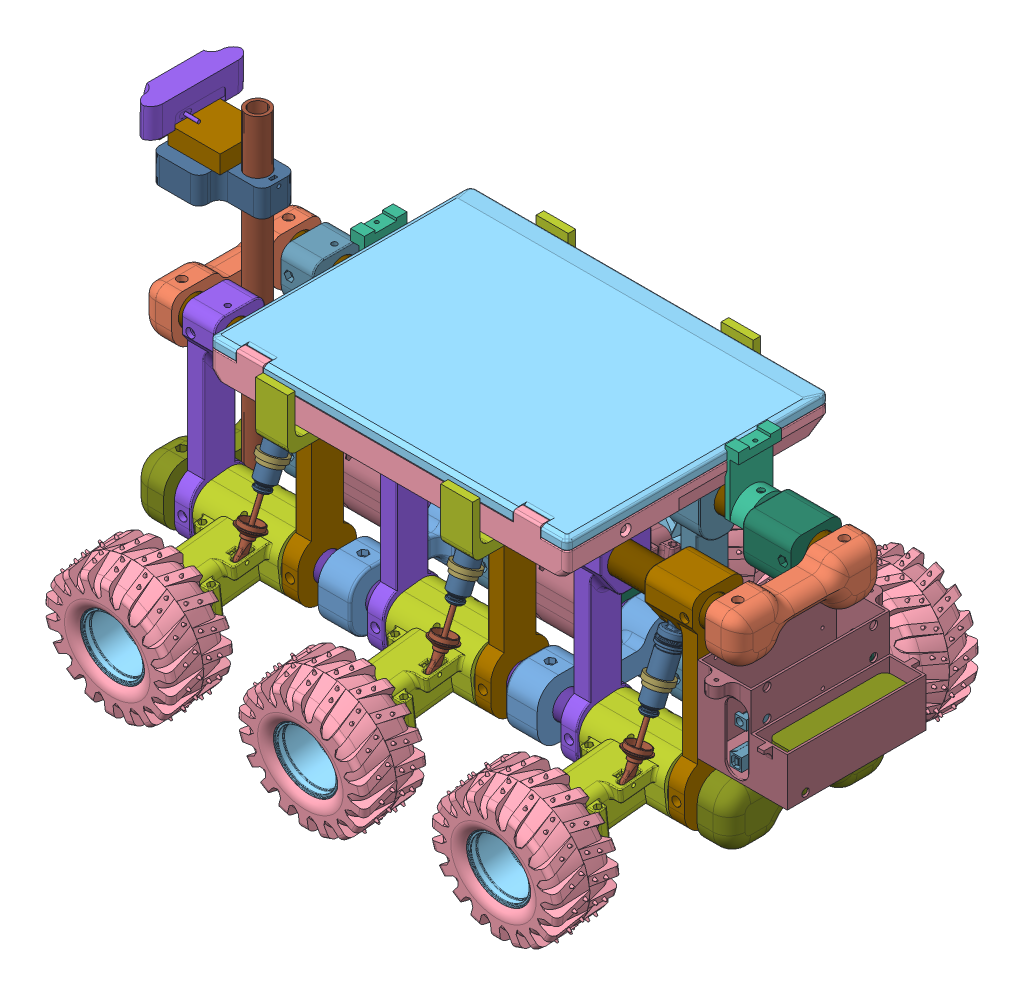
SolidWorks assembly main, configuration Default. Lengths in mm.
Overall size (673.66 443.73 565.58).
139 component instances, 35 part files, 83 mates.
Components (placement in the parent):
- ArmLeft-4: ArmLeft [Default] at (93.4852 140.0637 -467.7732) x (-1 0.000035 -0.000047) z (-0.000059 -0.599103 0.800672) size (161.81 187.08 295.86) (flexible)
  - Pololu_GearMotor_37Dmm-1: Pololu_GearMotor_37Dmm [Default] at (-21.99 -13.2291 218.2431) x (0.802337 0.514869 0.301937) z (0.000051 0.505806 -0.862647) size (51.49 51.49 82.3)
    - Pololu_ShaftGearMotor6mm-1: Pololu_ShaftGearMotor6mm [Default] at (9.8861 24.7007 16.6991) x (0.930815 0.36549 0) z (0 0 1) size (6 6 22)
    - Pololu_GearMotor_37Dmm-1: Pololu_GearMotor_37Dmm [Default] at (5.7082 30.3171 38.6991) x (-0.802354 -0.596848 0) z (0 0 -1) size (36.8 36.8 66.8)
  - BallBearing16412RS-1: BallBearing16412RS [Default] at (40.4709 -35.6395 240.9945) x (0.000054 0.419689 -0.907668) z (-1 0 -0.000059) size (50.8 50.8 14.29)
  - BallBearing16412RS-2: BallBearing16412RS [Default] at (-24.815 130.5388 213.2998) x (0.000042 -0.703492 -0.710704) z (-1 0 -0.000059) size (50.8 50.8 14.29)
  - Wheel-1: Wheel [Default] at (-14.2771 -41.8136 234.87) x (-0.938256 -0.298401 -0.175021) z (-0.000051 -0.505806 0.862647) size (126 126 62.61)
    - Tire-1: Tire [Varsayılan] at origin size (126 126 62.61)
    - tire_rim-1: tire_rim [Varsayılan] at (-6.6946 4.5427 -50) size (60 60 50)
  - HexWheelAdapter12_6mm-1: HexWheelAdapter12_6mm [Default] at (0.6857 -20.0769 202.4063) x (-0.115347 -0.856887 -0.502435) z (0.000051 0.505806 -0.862647) size (13.44 15.09 20)
  - MotorHolder1-1: MotorHolder1 [Default] at (-39.3143 -104.2251 201.6101) x (0.000051 0.505806 -0.862647) z (-1 0 -0.000059) size (107 55 80)
  - SuspensionLeft^ArmLeft-2: SuspensionLeft^ArmLeft [Default] at (43.4958 309.0701 -179.2653) x (-0.000047 -0.599103 0.800672) z (1 0 0.000059) size (55 192.5 30) (virtual)
  - Suspension-1: Suspension [Default] at (-42.2924 208.9334 -168.1241) x (0.000047 0.599103 -0.800672) z (-1 0 -0.000059) size (55 192.5 45)
  - ShockAbsorber-2: ShockAbsorber [Default] at (53.0553 208.387 150.3852) x (-0.438818 0.639066 0.631692) z (0.898576 0.312053 0.308519) size (127.39 56.5 78.28) (flexible)
    - ShockBody^ShockAbsorber-2: ShockBody^ShockAbsorber [Default] at (-177.2049 125.2783 -170.9566) x (-0.238903 0.964011 -0.116656) z (-0.43878 0 0.898594) size (22.02 74.55 22) (virtual)
    - Part4^ShockAbsorber-1: Part4^ShockAbsorber [Default] at (-177.4143 124.7536 -171.0588) x (0.238903 -0.964011 0.116656) z (0.43878 0 -0.898594) size (24 84.5 24) (virtual)
    - SpringAdjuster^ShockAbsorber-1: SpringAdjuster^ShockAbsorber [Default] at (-160.5945 130.1166 -162.8457) x (0.454686 -0.068682 -0.888) z (-0.207035 0.961561 -0.18038) size (24.5 8.5 24.5) (virtual)
    - Spring^ShockAbsorber-2: Spring^ShockAbsorber [Default] at (-75.3079 244.2893 -165.8313) x (-0.870144 -0.24964 -0.424888) z (0.492715 -0.424888 -0.759409) (virtual)
- ArmLeft-1: ArmLeft [Default] at (455.6977 21.2748 -292.1899) x (-1 -0.000003 0.000059) z (-0.000059 0.045994 -0.998942) size (177.35 270.46 190.89) (flexible)
  - Pololu_GearMotor_37Dmm-1: Pololu_GearMotor_37Dmm [Default] at (-21.9766 -0.1884 -7.3506) x (0.802352 -0.595823 0.035007) z (-0.000059 0.058573 0.998283) size (51.49 51.49 82.3)
    - Pololu_ShaftGearMotor6mm-1: Pololu_ShaftGearMotor6mm [Default] at (9.8861 24.7007 16.6991) x (0.930815 0.36549 0) z (0 0 1) size (6 6 22)
    - Pololu_GearMotor_37Dmm-1: Pololu_GearMotor_37Dmm [Default] at (5.7082 30.3171 38.6991) x (-0.802354 -0.596848 0) z (0 0 -1) size (36.8 36.8 66.8)
  - BallBearing16412RS-1: BallBearing16412RS [Default] at (40.4871 -19.893 -32.5036) x (-0.000056 0.32881 0.944396) z (-1 0 -0.000059) size (50.8 50.8 14.29)
  - BallBearing16412RS-2: BallBearing16412RS [Default] at (-24.8084 -120.1687 102.8691) x (-0.000001 0.99975 0.022349) z (-1 0 -0.000059) size (50.8 50.8 14.29)
  - Wheel-1: Wheel [Default] at (10.2673 23.7342 -37.6028) x (0.772436 0.634004 -0.037154) z (0.000059 -0.058573 -0.998283) size (126 126 62.61)
    - Tire-1: Tire [Varsayılan] at origin size (126 126 62.61)
    - tire_rim-1: tire_rim [Varsayılan] at (-6.6946 4.5427 -50) size (60 60 50)
  - HexWheelAdapter12_6mm-1: HexWheelAdapter12_6mm [Default] at (0.6975 14.3033 2.017) x (0.915591 -0.401418 0.023607) z (-0.000059 0.058573 0.998283) size (13.44 15.09 20)
  - MotorHolder1-1: MotorHolder1 [Default] at (-39.2997 84.7168 -44.0666) x (-0.000059 0.058573 0.998283) z (-1 0 -0.000059) size (107 55 80)
  - SuspensionLeft^ArmLeft-2: SuspensionLeft^ArmLeft [Default] at (43.4554 -44.446 502.7733) x (0.000059 0.045994 -0.998942) z (1 0 0.000059) size (55 192.5 30) (virtual)
  - Suspension-1: Suspension [Default] at (-42.3282 32.1448 437.3049) x (-0.000059 -0.045994 0.998942) z (-1 0 -0.000059) size (55 192.5 45)
  - ShockAbsorber-2: ShockAbsorber [Default] at (55.2647 -132.4405 202.2145) x (-0.43878 -0.898535 -0.010332) z (0.898595 -0.438752 -0.004979) size (123.94 75.92 76.38) (flexible)
    - ShockBody^ShockAbsorber-2: ShockBody^ShockAbsorber [Default] at (-179.6479 111.9864 -174.6116) x (-0.383839 0.904178 -0.187427) z (-0.43878 0 0.898594) size (22.02 74.55 22) (virtual)
    - Part4^ShockAbsorber-1: Part4^ShockAbsorber [Default] at (-180.0609 111.2784 -174.8133) x (0.383839 -0.904178 0.187427) z (0.43878 0 -0.898594) size (24 84.5 24) (virtual)
    - SpringAdjuster^ShockAbsorber-1: SpringAdjuster^ShockAbsorber [Default] at (-164.0284 119.9213 -166.9847) x (0.465012 -0.064419 -0.882957) z (-0.351603 0.901881 -0.250972) size (24.5 8.5 24.5) (virtual)
    - Spring^ShockAbsorber-2: Spring^ShockAbsorber [Default] at (-75.3079 244.2893 -165.8313) x (-0.870144 -0.24964 -0.424888) z (0.492715 -0.424888 -0.759409) (virtual)
- ArmLeft-2: ArmLeft [Default] at (274.2727 21.2748 -292.1899) x (-1 -0.000003 0.000059) z (-0.000059 0.045994 -0.998942) size (177.35 273.11 192.19) (flexible)
  - Pololu_GearMotor_37Dmm-1: Pololu_GearMotor_37Dmm [Default] at (-21.9767 -2.2828 -6.8251) x (0.802352 -0.595084 0.045897) z (-0.000059 0.07682 0.997045) size (51.49 51.49 82.3)
    - Pololu_ShaftGearMotor6mm-1: Pololu_ShaftGearMotor6mm [Default] at (9.8861 24.7007 16.6991) x (0.930815 0.36549 0) z (0 0 1) size (6 6 22)
    - Pololu_GearMotor_37Dmm-1: Pololu_GearMotor_37Dmm [Default] at (5.7082 30.3171 38.6991) x (-0.802354 -0.596848 0) z (0 0 -1) size (36.8 36.8 66.8)
  - BallBearing16412RS-1: BallBearing16412RS [Default] at (40.4871 -19.893 -32.5036) x (-0.000056 0.32881 0.944396) z (-1 0 -0.000059) size (50.8 50.8 14.29)
  - BallBearing16412RS-2: BallBearing16412RS [Default] at (-24.8084 -120.1687 102.8691) x (-0.000001 0.99975 0.022349) z (-1 0 -0.000059) size (50.8 50.8 14.29)
  - Wheel-1: Wheel [Default] at (10.2673 21.0826 -37.5097) x (0.772437 0.633218 -0.048742) z (0.000059 -0.07682 -0.997045) size (126 126 62.61)
    - Tire-1: Tire [Varsayılan] at origin size (126 126 62.61)
    - tire_rim-1: tire_rim [Varsayılan] at (-6.6946 4.5427 -50) size (60 60 50)
  - HexWheelAdapter12_6mm-1: HexWheelAdapter12_6mm [Default] at (0.6975 12.3777 2.276) x (0.91559 -0.40092 0.030944) z (-0.000059 0.07682 0.997045) size (13.44 15.09 20)
  - MotorHolder1-1: MotorHolder1 [Default] at (-39.2997 81.9368 -45.0877) x (-0.000059 0.07682 0.997045) z (-1 0 -0.000059) size (107 55 80)
  - SuspensionLeft^ArmLeft-2: SuspensionLeft^ArmLeft [Default] at (43.4554 -44.446 502.7733) x (0.000059 0.045994 -0.998942) z (1 0 0.000059) size (55 192.5 30) (virtual)
  - Suspension-1: Suspension [Default] at (-42.3282 32.1448 437.3049) x (-0.000059 -0.045994 0.998942) z (-1 0 -0.000059) size (55 192.5 45)
  - ShockAbsorber-2: ShockAbsorber [Default] at (22.1166 -132.4405 202.2126) x (-0.43878 -0.898535 -0.010332) z (0.898595 -0.438752 -0.004979) size (124.68 76.16 76.74) (flexible)
    - ShockBody^ShockAbsorber-2: ShockBody^ShockAbsorber [Default] at (-194.1718 111.9381 -144.8147) x (-0.382875 0.904684 -0.186957) z (-0.43878 0 0.898594) size (22.02 74.55 22) (virtual)
    - Part4^ShockAbsorber-1: Part4^ShockAbsorber [Default] at (-193.8798 111.6005 -144.6721) x (0.382875 -0.904684 0.186957) z (0.43878 0 -0.898594) size (24 84.5 24) (virtual)
    - SpringAdjuster^ShockAbsorber-1: SpringAdjuster^ShockAbsorber [Default] at (-178.5439 119.8524 -137.1837) x (0.464944 -0.064455 -0.882991) z (-0.350641 0.902385 -0.250502) size (24.5 8.5 24.5) (virtual)
    - Spring^ShockAbsorber-2: Spring^ShockAbsorber [Default] at (-75.3079 244.2893 -165.8313) x (-0.870144 -0.24964 -0.424888) z (0.492715 -0.424888 -0.759409) (virtual)
- Assem1^main-3: Assem1^main [Default] at (614.6197 202.709 -360.6526) x (0.43878 0.524054 0.729959) z (-0.898594 0.255894 0.356436) size (307.39 188.45 223.5) (virtual, flexible)
  - ShockAbsorber-1: ShockAbsorber [Default] at origin size (120.44 86.03 74.55) (flexible)
    - ShockBody^ShockAbsorber-2: ShockBody^ShockAbsorber [Default] at (-210.0974 33.2247 49.0022) x (0.462095 -0.857645 0.22564) z (-0.43878 0 0.898594) size (22.02 74.55 22) (virtual)
    - Part4^ShockAbsorber-1: Part4^ShockAbsorber [Default] at (-209.6006 34.0738 49.2448) x (-0.462095 0.857645 -0.22564) z (0.43878 0 -0.898594) size (24 84.5 24) (virtual)
    - SpringAdjuster^ShockAbsorber-1: SpringAdjuster^ShockAbsorber [Default] at (-224.9376 23.6143 41.7558) x (0.404743 0.061104 -0.912387) z (0.492182 -0.855465 0.161045) size (24.5 8.5 24.5) (virtual)
    - Spring^ShockAbsorber-2: Spring^ShockAbsorber [Default] at (-34.7976 -2.4454 -146.0502) x (0 1 0) z (0 0 -1) (virtual)
  - MotorHolder1-Mirror-1: MotorHolder1-Mirror [Default] at (-43.4227 -84.7919 111.9156) x (-0.778882 0.498694 -0.380325) z (0.43878 0 -0.898594) size (107 55 80)
  - BallBearing16412RS-1: BallBearing16412RS [Default] at (-127.0871 -123.0561 87.1989) x (-0.742239 0.56367 -0.362433) z (0.43878 0 -0.898594) size (50.8 50.8 14.29)
  - BallBearing16412RS-2: BallBearing16412RS [Default] at (-166.6314 -138.7613 140.5447) x (-0.66767 0.669274 -0.326021) z (0.43878 0 -0.898594) size (50.8 50.8 14.29)
  - PilarLeftMirror-1: PilarLeftMirror [Default] at (-608.0681 165.3148 -71.6688) x (0.729959 -0.583193 0.356436) z (-0.43878 0 0.898594) size (55 192.5 30)
  - PilarRightMirror-1: PilarRightMirror [Default] at (-419.6492 135.2573 -74.8966) x (-0.729959 0.583193 -0.356436) z (0.43878 0 -0.898594) size (55 192.5 45)
  - Pololu_GearMotor_37Dmm-1: Pololu_GearMotor_37Dmm [Default] at (-358.3928 -1.0018 27.8643) x (0.084596 -0.517335 -0.851592) z (0.778882 -0.498694 0.380325) size (51.49 51.49 82.3)
    - Pololu_ShaftGearMotor6mm-1: Pololu_ShaftGearMotor6mm [Default] at (9.8861 24.7007 16.6991) x (0.930815 0.36549 0) z (0 0 1) size (6 6 22)
    - Pololu_GearMotor_37Dmm-1: Pololu_GearMotor_37Dmm [Default] at (5.7082 30.3171 38.6991) x (-0.802354 -0.596848 0) z (0 0 -1) size (36.8 36.8 66.8)
  - HexWheelAdapter12_6mm-1: HexWheelAdapter12_6mm [Default] at (-334.2626 5.976 14.4134) x (0.000452 -0.605968 -0.795489) z (0.778882 -0.498694 0.380325) size (13.44 15.09 20)
  - Wheel-1: Wheel [Default] at (-357.6829 39.0349 3.1806) x (0.524924 0.850217 0.03982) z (-0.778882 0.498694 -0.380325) size (126 126 62.61)
    - Tire-1: Tire [Varsayılan] at origin size (126 126 62.61)
    - tire_rim-1: tire_rim [Varsayılan] at (-6.6946 4.5427 -50) size (60 60 50)
- Assem1^main-2: Assem1^main [Default] at (419.1947 176.319 -305.5999) x (0.43878 0.198516 0.876392) z (-0.898594 0.096934 0.427939) size (254.15 240.53 210.87) (virtual, flexible)
  - ShockAbsorber-1: ShockAbsorber [Default] at (357.3593 5.6816 -428.7668) size (96.34 119.79 62.78) (flexible)
    - ShockBody^ShockAbsorber-2: ShockBody^ShockAbsorber [Default] at (-603.8877 -2.3924 444.1635) x (0.727359 -0.587202 0.355167) z (-0.43878 0 0.898594) size (22.02 74.55 22) (virtual)
    - Part4^ShockAbsorber-1: Part4^ShockAbsorber [Default] at (-604.8865 -3.1688 443.6758) x (-0.727359 0.587202 -0.355167) z (0.43878 0 -0.898594) size (24 84.5 24) (virtual)
    - SpringAdjuster^ShockAbsorber-1: SpringAdjuster^ShockAbsorber [Default] at (-614.1511 -17.7106 439.1519) x (0.385844 0.041836 -0.921615) z (0.756772 -0.58571 0.290243) size (24.5 8.5 24.5) (virtual)
    - Spring^ShockAbsorber-2: Spring^ShockAbsorber [Default] at (-34.7976 -2.4454 -146.0502) x (0 1 0) z (0 0 -1) (virtual)
  - MotorHolder1-Mirror-1: MotorHolder1-Mirror [Default] at (-53.1417 -26.6364 91.3535) x (-0.896004 0.07587 -0.437516) z (0.43878 0 -0.898594) size (107 55 80)
  - BallBearing16412RS-1: BallBearing16412RS [Default] at (-135.4943 -159.2835 67.2773) x (-0.742239 0.56367 -0.362433) z (0.43878 0 -0.898594) size (50.8 50.8 14.29)
  - BallBearing16412RS-2: BallBearing16412RS [Default] at (-175.0386 -174.9888 120.6231) x (-0.66767 0.669274 -0.326021) z (0.43878 0 -0.898594) size (50.8 50.8 14.29)
  - PilarLeftMirror-1: PilarLeftMirror [Default] at (-661.7065 -34.8006 -113.6766) x (0.876392 -0.220918 0.427939) z (-0.43878 0 0.898594) size (55 192.5 30)
  - PilarRightMirror-1: PilarRightMirror [Default] at (-474.6757 2.8793 -117.5822) x (-0.876392 0.220918 -0.427939) z (0.43878 0 -0.898594) size (55 192.5 45)
  - Pololu_GearMotor_37Dmm-1: Pololu_GearMotor_37Dmm [Default] at (-372.4617 -89.0874 5.1782) x (0.311366 -0.595128 -0.74086) z (0.896004 -0.07587 0.437516) size (51.49 51.49 82.3)
    - Pololu_ShaftGearMotor6mm-1: Pololu_ShaftGearMotor6mm [Default] at (9.8861 24.7007 16.6991) x (0.930815 0.36549 0) z (0 0 1) size (6 6 22)
    - Pololu_GearMotor_37Dmm-1: Pololu_GearMotor_37Dmm [Default] at (5.7082 30.3171 38.6991) x (-0.802354 -0.596848 0) z (0 0 -1) size (36.8 36.8 66.8)
  - HexWheelAdapter12_6mm-1: HexWheelAdapter12_6mm [Default] at (-352.4252 -75.9832 -10.2716) x (0.266074 -0.697089 -0.665786) z (0.896004 -0.07587 0.437516) size (13.44 15.09 20)
  - Wheel-1: Wheel [Default] at (-386.379 -57.3679 -26.6479) x (0.152236 0.978067 -0.142162) z (-0.896004 0.07587 -0.437516) size (126 126 62.61)
    - Tire-1: Tire [Varsayılan] at origin size (126 126 62.61)
    - tire_rim-1: tire_rim [Varsayılan] at (-6.6946 4.5427 -50) size (60 60 50)
- Assem1^main-1: Assem1^main [Default] at (252.4072 174.6911 -303.4834) x (0.43878 0.183261 0.879709) z (-0.898594 0.089486 0.429559) size (252.1 239.77 209.46) (virtual, flexible)
  - ShockAbsorber-1: ShockAbsorber [Default] at origin size (94.39 119.64 61.83) (flexible)
    - ShockBody^ShockAbsorber-2: ShockBody^ShockAbsorber [Default] at (-254.4148 1.6325 27.3622) x (0.735418 -0.574636 0.359102) z (-0.43878 0 0.898594) size (22.02 74.55 22) (virtual)
    - Part4^ShockAbsorber-1: Part4^ShockAbsorber [Default] at (-254.7467 1.8789 27.2001) x (-0.735418 0.574636 -0.359102) z (0.43878 0 -0.898594) size (24 84.5 24) (virtual)
    - SpringAdjuster^ShockAbsorber-1: SpringAdjuster^ShockAbsorber [Default] at (-264.4645 -13.8601 22.4549) x (0.38527 0.04094 -0.921895) z (0.76481 -0.573175 0.294168) size (24.5 8.5 24.5) (virtual)
    - Spring^ShockAbsorber-2: Spring^ShockAbsorber [Default] at (-34.7976 -2.4454 -146.0502) x (0 1 0) z (0 0 -1) (virtual)
  - MotorHolder1-Mirror-1: MotorHolder1-Mirror [Default] at (-59.2886 -30.3009 104.1683) x (-0.895318 0.085316 -0.437181) z (0.43878 0 -0.898594) size (107 55 80)
  - BallBearing16412RS-1: BallBearing16412RS [Default] at (-142.0621 -160.9812 79.8867) x (-0.742239 0.56367 -0.362433) z (0.43878 0 -0.898594) size (50.8 50.8 14.29)
  - BallBearing16412RS-2: BallBearing16412RS [Default] at (-181.6064 -176.6864 133.2324) x (-0.66767 0.669274 -0.326021) z (0.43878 0 -0.898594) size (50.8 50.8 14.29)
  - PilarLeftMirror-1: PilarLeftMirror [Default] at (-668.8755 -43.9663 -101.3608) x (0.879709 -0.203942 0.429559) z (-0.43878 0 0.898594) size (55 192.5 30)
  - PilarRightMirror-1: PilarRightMirror [Default] at (-482.4555 -3.4022 -105.5646) x (-0.879709 0.203942 -0.429559) z (0.43878 0 -0.898594) size (55 192.5 45)
  - Pololu_GearMotor_37Dmm-1: Pololu_GearMotor_37Dmm [Default] at (-379.1273 -89.6715 17.7397) x (0.3063 -0.594672 -0.743334) z (0.895318 -0.085316 0.437181) size (51.49 51.49 82.3)
    - Pololu_ShaftGearMotor6mm-1: Pololu_ShaftGearMotor6mm [Default] at (9.8861 24.7007 16.6991) x (0.930815 0.36549 0) z (0 0 1) size (6 6 22)
    - Pololu_GearMotor_37Dmm-1: Pololu_GearMotor_37Dmm [Default] at (5.7082 30.3171 38.6991) x (-0.802354 -0.596848 0) z (0 0 -1) size (36.8 36.8 66.8)
  - HexWheelAdapter12_6mm-1: HexWheelAdapter12_6mm [Default] at (-358.9796 -76.6742 2.3442) x (0.26014 -0.696555 -0.668684) z (0.895318 -0.085316 0.437181) size (13.44 15.09 20)
  - Wheel-1: Wheel [Default] at (-392.7734 -57.7025 -13.9539) x (0.160562 0.977317 -0.138096) z (-0.895318 0.085316 -0.437181) size (126 126 62.61)
    - Tire-1: Tire [Varsayılan] at origin size (126 126 62.61)
    - tire_rim-1: tire_rim [Varsayılan] at (-6.6946 4.5427 -50) size (60 60 50)
- UnionBottom^main-1: UnionBottom^main [Default] at (-5 107.1759 -896.898) x (0 0 1) z (1 0 0) size (155 55 31.72) (virtual)
- BaseTubeLeft-2: BaseTubeLeft [Default] at (550 176.5134 -592.0813) x (-1 0 0) z (0 0.580212 0.814466) size (550 25.4 25.4)
- BaseTubeLeft-1: BaseTubeLeft [Default] at (0 208.2023 -402.5015) x (1 0 0) z (0 -0.060997 -0.998138) size (550 25.4 25.4)
- PVC pipe-2: PVC pipe [Default] at (0 198.6865 -498.2364) x (0 0.859457 0.511208) z (0 0.511208 -0.859457) size (27 550 27)
- PVC pipe-1: PVC pipe [Default] at (0 198.6865 -398.2364) x (0 -0.312384 0.949956) z (0 0.949956 0.312384) size (27 550 27)
- UnionBottomMiddle^main-4: UnionBottomMiddle^main [Default] at (169.6692 0.1971 0.4252) x (0 0 -1) z (1 0 0) size (155 55 30) (virtual)
- UnionBottomMiddle^main-5: UnionBottomMiddle^main [Default] at (375.1144 0.1971 -896.898) x (0 0 1) z (-1 0 0) size (155 55 30) (virtual)
- UnionBottom^main-2: UnionBottom^main [Default] at (555 107.1759 0.4252) x (0 0 -1) z (-1 0 0) size (155 55 31.72) (virtual)
- UnionTop^main-1: UnionTop^main [Default] at (-5 142.6535 0.4252) x (0 0 -1) z (1 0 0) size (140 47.5 31.7) (virtual)
- UnionTop^main-2: UnionTop^main [Default] at (555 142.6535 -896.898) x (0 0 1) z (-1 0 0) size (140 47.5 31.7) (virtual)
- UnionTopMiddle1^main-1: UnionTopMiddle1^main [Default] at (278.2515 142.6535 -896.898) x (0 0 1) z (-1 0 0) size (140 47.5 20) (virtual)
- DellLaptop^main-1: DellLaptop^main [Default] at (263.7311 218.4114 -520.2241) size (335 33 245) (virtual)
  - Body^DellLaptop_main-1: Body^DellLaptop_main [Default] at (0 5.2751 30.0436) x (1 0 0) z (0 1 0) size (335 245 33) (virtual)
  - Screen^DellLaptop_main-1: Screen^DellLaptop_main [Default] at (-2.5725 5.2751 34.467) size (335 10 245) (virtual)
- LaptopHolder^main-3: LaptopHolder^main [Default] at (105.575 198.6865 -498.2364) x (0 0 -1) z (1 0 0) size (40 60 20) (virtual)
- LaptopHolderSides^main-1: LaptopHolderSides^main [Default] at (168.6816 198.7597 -398.3449) x (0 0 -1) z (1 0 0) size (105 63.33 30) (virtual)
- CameraMount-1: CameraMount [Default] at (59.412 265.1828 -446.1439) x (0 0 1) z (-0.999878 0.015593 0) size (92.68 44.39 65.89)
  - LogitechC920_camera-1: LogitechC920_camera [Default] at (-48.8625 43.709 78.1959) size (92.68 27.69 37.04)
  - Part1^CameraMount-1: Part1^CameraMount [Default] at (2.5933 43.6448 94.029) x (1 0 0) z (0 -0.015593 0.999878) size (49 21 59.86) (virtual)
- CameraHolder^main-1: CameraHolder^main [Default] at (-66.4975 268.6865 25.215) x (1 0 0) z (0 1 0) size (85 70 25) (virtual)
- PVC pipe1.5-1: PVC pipe1.5 [Default] at (35.715 43.6865 -448.0214) x (-0.835974 0 0.548768) z (-0.548768 0 -0.835974) size (21.43 300 21.43)
- hex bolt_ai-2: hex bolt_ai [HBOLT 0.2500-20x1.5x0.75-N] at (-6.785 263.9113 -448.0214) x (0 1 0) z (-0.500212 0 0.865903) size (42.88 12.85 11.13)
- LaptopHolder^main-7: LaptopHolder^main [Default] at (443.478 198.6865 -498.2364) x (0 0 1) z (-1 0 0) size (40 60 20) (virtual)
- LaptopHolderSides^main-2: LaptopHolderSides^main [Default] at (342.0881 198.7597 -398.3449) x (0 0 -1) z (1 0 0) size (105 63.33 30) (virtual)
- LaptopHolderSides^main-3: LaptopHolderSides^main [Default] at (372.0881 198.7597 -498.1279) x (0 0 1) z (-1 0 0) size (105 63.33 30) (virtual)
- LaptopHolderSides^main-4: LaptopHolderSides^main [Default] at (198.6816 198.7597 -498.1279) x (0 0 1) z (-1 0 0) size (105 63.33 30) (virtual)
- ElectronicBox-2: ElectronicBox [Default] at (561.2891 -1.6692 -898.3048) x (0 0 1) z (-1 0 0) size (160 80 84)
  - ElectronicBox-1: ElectronicBox [Default] at (0 0 -1.7109) size (160 80 84)
  - ArduinoMega-1: ArduinoMega [Default] at (461.3116 117.7793 3.6985) x (1 0 0) z (0 0 -1) size (107.95 53.42 12.95)
  - switch-1: switch [Default] at (399.7684 121.8057 14.8891) x (0 0 1) z (-1 0 0) size (28 28 28.82)
  - Battery^ElectronicBox-1: Battery^ElectronicBox [Default] at (106.6086 15.5367 -33.917) size (110 36 27) (virtual)
Mates (geometry in assembly coordinates):
- Concentric26: concentric aligned: cylinder of BaseTubeLeft-1 through (550 53.6865 -398.2364) axis (-1 0 0) radius 12.7; cylinder of ArmLeft-1/BallBearing16412RS-1 through (429.5 53.6865 -398.2364) axis (-1 0 0) radius 12.7
- Concentric27: concentric aligned: cylinder of BaseTubeLeft-1 through (550 53.6865 -398.2364) axis (-1 0 0) radius 12.7; cylinder of ArmLeft-1/BallBearing16412RS-2 through (494.7875 53.6865 -398.2364) axis (-1 0 0) radius 12.7
- Coincident8: coincident aligned: plane of BaseTubeLeft-1 through (0 53.6865 -398.2364) normal (-1 0 0); plane of PVC pipe-1 through (0 198.6865 -398.2364) normal (-1 0 0)
- Distance15: distance = 55 mm aligned: plane of ArmLeft-1/MotorHolder1-1 through (495 103.8753 -244.2758) normal (1 0 0); plane of BaseTubeLeft-1 through (550 53.6865 -398.2364) normal (1 0 0)
- Coincident17: coincident aligned: plane of BaseTubeLeft-1 through (0 53.6865 -398.2364) normal (-1 0 0); plane of BaseTubeLeft-2 through (0 53.6865 -498.2364) normal (-1 0 0)
- Coincident27: coincident aligned: plane of PVC pipe-1 through (0 198.6865 -398.2364) normal (-1 0 0); plane of PVC pipe-2 through (0 198.6865 -498.2364) normal (-1 0 0)
- Concentric930: concentric anti-aligned: cylinder of BaseTubeLeft-2 through (0 53.6865 -498.2364) axis (1 0 0) radius 12.7; cylinder of UnionBottomMiddle^main-4 through (199.6692 53.6865 -498.2364) axis (-1 0 0) radius 13
- Concentric931: concentric aligned: cylinder of BaseTubeLeft-1 through (550 53.6865 -398.2364) axis (-1 0 0) radius 12.7; cylinder of UnionBottomMiddle^main-4 through (199.6692 53.6865 -398.2364) axis (-1 0 0) radius 13
- Concentric941: concentric aligned: cylinder of BaseTubeLeft-2 through (0 53.6865 -498.2364) axis (1 0 0) radius 12.7; cylinder of UnionBottomMiddle^main-5 through (345.1144 53.6865 -498.2364) axis (1 0 0) radius 13
- Concentric942: concentric anti-aligned: cylinder of BaseTubeLeft-1 through (550 53.6865 -398.2364) axis (-1 0 0) radius 12.7; cylinder of UnionBottomMiddle^main-5 through (345.1144 53.6865 -398.2364) axis (1 0 0) radius 13
- Concentric947: concentric anti-aligned: cylinder of UnionBottom^main-1 through (30 53.6865 -498.2364) axis (-1 0 0) radius 13; cylinder of BaseTubeLeft-2 through (0 53.6865 -498.2364) axis (1 0 0) radius 12.7
- Concentric948: concentric aligned: cylinder of UnionBottom^main-1 through (30 53.6865 -398.2364) axis (-1 0 0) radius 13; cylinder of BaseTubeLeft-1 through (550 53.6865 -398.2364) axis (-1 0 0) radius 12.7
- Coincident67: coincident anti-aligned: plane of UnionBottom^main-1 through (0 107.1759 -896.898) normal (1 0 0); plane of BaseTubeLeft-2 through (0 53.6865 -498.2364) normal (-1 0 0)
- Concentric949: concentric anti-aligned: cylinder of BaseTubeLeft-1 through (550 53.6865 -398.2364) axis (-1 0 0) radius 12.7; cylinder of UnionBottom^main-2 through (520 53.6865 -398.2364) axis (1 0 0) radius 13
- Concentric950: concentric aligned: cylinder of BaseTubeLeft-2 through (0 53.6865 -498.2364) axis (1 0 0) radius 12.7; cylinder of UnionBottom^main-2 through (520 53.6865 -498.2364) axis (1 0 0) radius 13
- Coincident68: coincident anti-aligned: plane of BaseTubeLeft-2 through (550 53.6865 -498.2364) normal (1 0 0); plane of UnionBottom^main-2 through (550 107.1759 0.4252) normal (-1 0 0)
- Concentric952: concentric aligned: cylinder of PVC pipe-2 through (550 198.6865 -498.2364) axis (-1 0 0) radius 13.5; cylinder of UnionTop^main-1 through (30 198.6865 -498.2364) axis (-1 0 0) radius 13.75
- Coincident69: coincident anti-aligned: plane of PVC pipe-2 through (0 198.6865 -498.2364) normal (-1 0 0); plane of UnionTop^main-1 through (0 142.6535 0.4252) normal (1 0 0)
- Concentric953: concentric anti-aligned: cylinder of PVC pipe-1 through (550 198.6865 -398.2364) axis (-1 0 0) radius 13.5; cylinder of UnionTop^main-2 through (520 198.6865 -398.2364) axis (1 0 0) radius 13.75
- Concentric955: concentric anti-aligned: cylinder of UnionTop^main-2 through (520 198.6865 -498.2364) axis (1 0 0) radius 13.75; cylinder of PVC pipe-2 through (550 198.6865 -498.2364) axis (-1 0 0) radius 13.5
- Coincident71: coincident anti-aligned: plane of PVC pipe-1 through (550 198.6865 -398.2364) normal (1 0 0); plane of UnionTop^main-2 through (550 142.6535 -896.898) normal (-1 0 0)
- Concentric956: concentric aligned: cylinder of PVC pipe-1 through (550 198.6865 -398.2364) axis (-1 0 0) radius 13.5; cylinder of UnionTop^main-1 through (30 198.6865 -398.2364) axis (-1 0 0) radius 13.75
- Concentric957: concentric anti-aligned: cylinder of PVC pipe-2 through (550 198.6865 -498.2364) axis (-1 0 0) radius 13.5; cylinder of UnionTopMiddle1^main-1 through (248.2515 198.6865 -498.2364) axis (1 0 0) radius 13.75
- Concentric958: concentric anti-aligned: cylinder of PVC pipe-1 through (550 198.6865 -398.2364) axis (-1 0 0) radius 13.5; cylinder of UnionTopMiddle1^main-1 through (248.2515 198.6865 -398.2364) axis (1 0 0) radius 13.75
- Concentric959: concentric anti-aligned: cylinder of BaseTubeLeft-2 through (0 53.6865 -498.2364) axis (1 0 0) radius 12.7; cylinder of Assem1^main-1/MotorHolder1-Mirror-1 through (67.2875 53.6865 -498.2364) axis (-1 0 0) radius 25.425
- Concentric960: concentric aligned: cylinder of BaseTubeLeft-2 through (0 53.6865 -498.2364) axis (1 0 0) radius 12.7; cylinder of Assem1^main-1/PilarLeftMirror-1 through (35 53.6865 -498.2364) axis (1 0 0) radius 13
- Concentric961: concentric anti-aligned: cylinder of Assem1^main-1/PilarLeftMirror-1 through (35 198.6865 -498.2364) axis (1 0 0) radius 13.75; cylinder of PVC pipe-2 through (550 198.6865 -498.2364) axis (-1 0 0) radius 13.5
- Concentric962: concentric anti-aligned: cylinder of BaseTubeLeft-2 through (0 53.6865 -498.2364) axis (1 0 0) radius 12.7; cylinder of Assem1^main-1/PilarRightMirror-1 through (150.575 53.6865 -498.2364) axis (-1 0 0) radius 13
- Concentric963: concentric aligned: cylinder of Assem1^main-1/PilarRightMirror-1 through (150.575 198.6865 -498.2364) axis (-1 0 0) radius 13.75; cylinder of PVC pipe-2 through (550 198.6865 -498.2364) axis (-1 0 0) radius 13.5
- Concentric978: concentric anti-aligned: cylinder of ArmLeft-2/SuspensionLeft^ArmLeft-2 through (215.7875 53.6865 -398.2364) axis (1 0 0) radius 13; cylinder of BaseTubeLeft-1 through (550 53.6865 -398.2364) axis (-1 0 0) radius 12.7
- Concentric981: concentric anti-aligned: cylinder of Assem1^main-3/PilarRightMirror-1 through (512.7875 53.6865 -498.2364) axis (-1 0 0) radius 13; cylinder of BaseTubeLeft-2 through (0 53.6865 -498.2364) axis (1 0 0) radius 12.7
- Concentric982: concentric aligned: cylinder of Assem1^main-3/PilarRightMirror-1 through (512.7875 198.6865 -498.2364) axis (-1 0 0) radius 13.75; cylinder of PVC pipe-2 through (550 198.6865 -498.2364) axis (-1 0 0) radius 13.5
- Concentric983: concentric anti-aligned: cylinder of Assem1^main-2/PilarLeftMirror-1 through (216 198.6865 -498.2364) axis (1 0 0) radius 13.75; cylinder of PVC pipe-2 through (550 198.6865 -498.2364) axis (-1 0 0) radius 13.5
- Concentric984: concentric anti-aligned: cylinder of Assem1^main-2/PilarRightMirror-1 through (331.575 53.6865 -498.2364) axis (-1 0 0) radius 13; cylinder of BaseTubeLeft-2 through (0 53.6865 -498.2364) axis (1 0 0) radius 12.7
- Concentric991: concentric anti-aligned: cylinder of PVC pipe-2 through (550 198.6865 -498.2364) axis (-1 0 0) radius 13.5; cylinder of LaptopHolder^main-3 through (85.575 198.6865 -498.2364) axis (1 0 0) radius 13.75
- Parallel31: parallel aligned: plane of Assem1^main-1/PilarLeftMirror-1 through (35 0 -518.2364) normal (0 0 -1); plane of CameraMount-1/Part1^CameraMount-1 through (-36.785 314.6865 -470.5214) normal (0 0 -1)
- Parallel32: parallel anti-aligned: plane of Assem1^main-1/PilarLeftMirror-1 through (35 218.6865 -100) normal (0 1 0); plane of CameraMount-1/Part1^CameraMount-1 through (-36.785 293.6865 -425.5214) normal (0 -1 0)
- Parallel36: parallel aligned: plane of Assem1^main-1/PilarLeftMirror-1 through (35 0 -100) normal (-1 0 0); plane of CameraHolder^main-1 through (-29.285 293.6865 -413.0214) normal (-1 0 0)
- Parallel37: parallel aligned: plane of PVC pipe1.5-1 through (35.715 43.6865 -448.0214) normal (0 -1 0); plane of Assem1^main-1/PilarLeftMirror-1 through (35 26.1865 -100) normal (0 -1 0)
- Concentric9936: concentric anti-aligned: cylinder of CameraMount-1/Part1^CameraMount-1 through (-6.785 298.6865 -448.0214) axis (0 -1 0) radius 3.175; cylinder of CameraHolder^main-1 through (-6.785 268.6865 -448.0214) axis (0 1 0) radius 3.175
- Coincident98: coincident anti-aligned: plane of CameraMount-1/Part1^CameraMount-1 through (-36.785 293.6865 -425.5214) normal (0 -1 0); plane of CameraHolder^main-1 through (-66.4975 293.6865 25.215) normal (0 1 0)
- Concentric9937: concentric aligned: cylinder of CameraHolder^main-1 through (35.715 293.6865 -448.0214) axis (0 -1 0) radius 10.85; cylinder of PVC pipe1.5-1 through (35.715 343.6865 -448.0214) axis (0 -1 0) radius 10.715
- Tangent1: tangent anti-aligned: cylinder of UnionBottom^main-1 through (25 23.6865 -457.5077) axis (-1 0 0) radius 20; plane of PVC pipe1.5-1 through (35.715 43.6865 -448.0214) normal (0 -1 0)
- Tangent2: tangent anti-aligned: plane of UnionBottom^main-1 through (25 107.1759 -896.898) normal (1 0 0); cylinder of PVC pipe1.5-1 through (35.715 343.6865 -448.0214) axis (0 -1 0) radius 10.715
- Distance38: distance = 24.5 mm anti-aligned: cylinder of PVC pipe1.5-1 through (35.715 343.6865 -448.0214) axis (0 -1 0) radius 10.715; plane of Assem1^main-1/PilarLeftMirror-1 through (35 0 -483.2364) normal (0 0 1)
- Coincident99: coincident anti-aligned: plane of CameraHolder^main-1 through (-66.4975 268.6865 25.215) normal (0 -1 0); plane of hex bolt_ai-2 through (-12.3468 268.6865 -451.2343) normal (0 1 0)
- Concentric9941: concentric aligned: cylinder of PVC pipe-2 through (550 198.6865 -498.2364) axis (-1 0 0) radius 13.5; cylinder of LaptopHolder^main-7 through (463.478 198.6865 -498.2364) axis (-1 0 0) radius 13.75
- Parallel39: parallel aligned: plane of DellLaptop^main-1/Body^DellLaptop_main-1 through (110.575 246.6865 -573.2364) normal (0 0 -1); plane of LaptopHolder^main-7 through (448.478 198.6865 -518.2364) normal (0 0 -1)
- Concentric9942: concentric aligned: cylinder of PVC pipe-1 through (550 198.6865 -398.2364) axis (-1 0 0) radius 13.5; cylinder of LaptopHolderSides^main-2 through (372.0881 198.6865 -398.2364) axis (-1 0 0) radius 13.75
- Parallel40: parallel aligned: plane of LaptopHolderSides^main-1 through (198.6816 198.7597 -313.2364) normal (0 0 1); plane of LaptopHolderSides^main-2 through (372.0881 198.7597 -313.2364) normal (0 0 1)
- Concentric9943: concentric anti-aligned: cylinder of PVC pipe-2 through (550 198.6865 -498.2364) axis (-1 0 0) radius 13.5; cylinder of LaptopHolderSides^main-3 through (342.0881 198.6865 -498.2364) axis (1 0 0) radius 13.75
- Parallel41: parallel anti-aligned: plane of DellLaptop^main-1/Screen^DellLaptop_main-1 through (110.575 256.6865 -573.2364) normal (0 0 -1); plane of LaptopHolderSides^main-3 through (342.0881 198.7597 -576.2364) normal (0 0 1)
- Concentric9944: concentric anti-aligned: cylinder of PVC pipe-2 through (550 198.6865 -498.2364) axis (-1 0 0) radius 13.5; cylinder of LaptopHolderSides^main-4 through (168.6816 198.6865 -498.2364) axis (1 0 0) radius 13.75
- Parallel42: parallel anti-aligned: plane of DellLaptop^main-1/Body^DellLaptop_main-1 through (110.575 246.6865 -573.2364) normal (0 0 -1); plane of LaptopHolderSides^main-4 through (168.6816 198.7597 -576.2364) normal (0 0 1)
- Coincident113: coincident anti-aligned: plane of ArmLeft-1/Suspension-1 through (513 73.4989 -727.5561) normal (1 0 0); plane of ElectronicBox-2/ElectronicBox-1 through (513 -1.6692 -898.3048) normal (-1 0 0)
- Concentric9947: concentric anti-aligned: cylinder of ArmLeft-4/SuspensionLeft^ArmLeft-2 through (35 53.6865 -398.2364) axis (1 0 0) radius 13; cylinder of BaseTubeLeft-1 through (550 53.6865 -398.2364) axis (-1 0 0) radius 12.7
- Concentric9948: concentric anti-aligned: cylinder of ArmLeft-4/SuspensionLeft^ArmLeft-2 through (35 198.6865 -398.2364) axis (1 0 0) radius 13.75; cylinder of PVC pipe-1 through (550 198.6865 -398.2364) axis (-1 0 0) radius 13.5
- Coincident114: coincident aligned: plane of ArmLeft-4/SuspensionLeft^ArmLeft-2 through (35 26.1865 -796.4728) normal (0 -1 0); plane of Assem1^main-1/PilarLeftMirror-1 through (35 26.1865 -100) normal (0 -1 0)
- Concentric9949: concentric anti-aligned: cylinder of ArmLeft-2/SuspensionLeft^ArmLeft-2 through (215.7875 198.6865 -398.2364) axis (1 0 0) radius 13.75; cylinder of PVC pipe-1 through (550 198.6865 -398.2364) axis (-1 0 0) radius 13.5
- Concentric9951: concentric anti-aligned: cylinder of ArmLeft-1/SuspensionLeft^ArmLeft-2 through (397.2125 198.6865 -398.2364) axis (1 0 0) radius 13.75; cylinder of PVC pipe-1 through (550 198.6865 -398.2364) axis (-1 0 0) radius 13.5
- Distance41: distance = 10 mm anti-aligned: plane of ArmLeft-4/SuspensionLeft^ArmLeft-2 through (35 0 -796.4728) normal (-1 0 0); plane of UnionBottom^main-1 through (25 107.1759 -896.898) normal (1 0 0)
- Distance42: distance = 10 mm anti-aligned: plane of Assem1^main-1/PilarLeftMirror-1 through (35 0 -100) normal (-1 0 0); plane of UnionBottom^main-1 through (25 107.1759 -896.898) normal (1 0 0)
- Concentric9952: concentric aligned: cylinder of PVC pipe-1 through (550 198.6865 -398.2364) axis (-1 0 0) radius 13.5; cylinder of LaptopHolderSides^main-1 through (198.6816 198.6865 -398.2364) axis (-1 0 0) radius 13.75
- Coincident118: coincident aligned: plane of ArmLeft-2/Suspension-1 through (331.575 218.6865 -727.5561) normal (0 1 0); plane of LaptopHolderSides^main-1 through (198.6816 218.6865 -398.3449) normal (0 1 0)
- Coincident119: coincident aligned: plane of Assem1^main-2/PilarRightMirror-1 through (331.575 218.6865 -168.9168) normal (0 1 0); plane of LaptopHolderSides^main-3 through (342.0881 218.6865 -498.1279) normal (0 1 0)
- Coincident120: coincident aligned: plane of LaptopHolderSides^main-1 through (198.6816 198.7597 -398.3449) normal (1 0 0); plane of LaptopHolderSides^main-4 through (198.6816 198.7597 -498.1279) normal (1 0 0)
- Coincident121: coincident aligned: plane of LaptopHolderSides^main-2 through (372.0881 198.7597 -398.3449) normal (1 0 0); plane of LaptopHolderSides^main-3 through (372.0881 198.7597 -498.1279) normal (1 0 0)
- Coincident122: coincident aligned: plane of LaptopHolder^main-3 through (100.575 198.6865 -518.2364) normal (0 0 -1); plane of LaptopHolder^main-7 through (448.478 198.6865 -518.2364) normal (0 0 -1)
- Distance43: distance = 5 mm anti-aligned: plane of DellLaptop^main-1/Body^DellLaptop_main-1 through (263.7311 223.6865 -490.1805) normal (0 -1 0); plane of LaptopHolderSides^main-2 through (372.0881 218.6865 -398.3449) normal (0 1 0)
- Distance44: distance = 8 mm anti-aligned: plane of LaptopHolderSides^main-1 through (198.6816 198.7597 -320.2364) normal (0 0 -1); plane of DellLaptop^main-1/Body^DellLaptop_main-1 through (110.575 246.6865 -328.2364) normal (0 0 1)
- Concentric9953: concentric anti-aligned: cylinder of CameraHolder^main-1 through (-6.785 268.6865 -448.0214) axis (0 1 0) radius 3.175; cylinder of hex bolt_ai-2 through (-6.785 263.9113 -448.0214) axis (0 -1 0) radius 3.175
- Distance45: distance = 50 mm anti-aligned: plane of CameraHolder^main-1 through (-66.4975 268.6865 25.215) normal (0 -1 0); plane of Assem1^main-1/PilarLeftMirror-1 through (35 218.6865 -100) normal (0 1 0)
- Distance46: distance = 5 mm anti-aligned: plane of ElectronicBox-2/ElectronicBox-1 through (513 86.1865 -513.2364) normal (0 -1 0); plane of UnionBottom^main-2 through (525 81.1865 0.4252) normal (0 1 0)
- Coincident126: coincident aligned: plane of Assem1^main-3/PilarRightMirror-1 through (512.7875 73.4989 -513.2364) normal (0 0 -1); plane of ElectronicBox-2/ElectronicBox-1 through (513 166.1865 -513.2364) normal (0 0 -1)
- Distance47: distance = 65 mm anti-aligned: plane of ArmLeft-2/SuspensionLeft^ArmLeft-2 through (215.7875 0 -796.4728) normal (-1 0 0); plane of ArmLeft-4/Suspension-1 through (150.7875 73.4989 -727.5561) normal (1 0 0)
- Concentric9954: concentric anti-aligned: cylinder of Assem1^main-3/PilarLeftMirror-1 through (397.2125 198.6865 -498.2364) axis (1 0 0) radius 13.75; cylinder of PVC pipe-2 through (550 198.6865 -498.2364) axis (-1 0 0) radius 13.5
- Coincident130: coincident aligned: plane of ArmLeft-1/SuspensionLeft^ArmLeft-2 through (397.2125 0 -796.4728) normal (-1 0 0); plane of Assem1^main-3/PilarLeftMirror-1 through (397.2125 0 -100) normal (-1 0 0)
- Parallel46: parallel aligned: plane of ArmLeft-4/SuspensionLeft^ArmLeft-2 through (35 0 -796.4728) normal (-1 0 0); plane of Assem1^main-1/PilarLeftMirror-1 through (35 0 -100) normal (-1 0 0)
- Distance49: distance = 5 mm anti-aligned: plane of LaptopHolder^main-3 through (105.575 198.6865 -498.2364) normal (1 0 0); plane of DellLaptop^main-1/Body^DellLaptop_main-1 through (110.575 246.6865 -573.2364) normal (-1 0 0)
- Coincident135: coincident anti-aligned: plane of Assem1^main-1/PilarRightMirror-1 through (105.575 176.6865 -496.4681) normal (-1 0 0); plane of LaptopHolder^main-3 through (105.575 198.6865 -498.2364) normal (1 0 0)
- Parallel47: parallel aligned: plane of DellLaptop^main-1/Screen^DellLaptop_main-1 through (261.1585 256.6865 -485.7572) normal (0 1 0); plane of assembly through (0 0 0) normal (0 1 0)
- Coincident137: coincident aligned: plane of ArmLeft-2/Suspension-1 through (331.575 73.4989 -727.5561) normal (1 0 0); plane of Assem1^main-2/PilarRightMirror-1 through (331.575 73.4989 -168.9168) normal (1 0 0)
- Concentric9957: concentric aligned: cylinder of Assem1^main-2/PilarLeftMirror-1 through (216 53.6865 -498.2364) axis (1 0 0) radius 13; cylinder of BaseTubeLeft-2 through (0 53.6865 -498.2364) axis (1 0 0) radius 12.7
